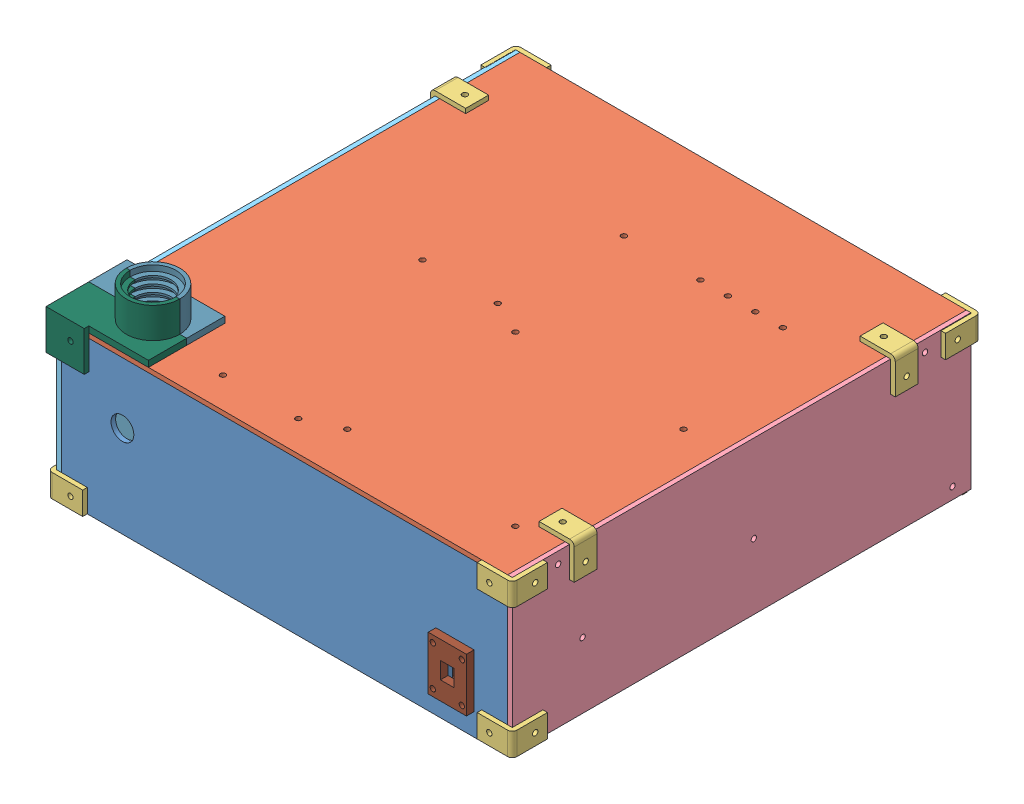
SolidWorks assembly Assem1, configuration Default. Lengths in mm.
Overall size (305.4 127.48 308.43).
27 component instances, 15 part files, 54 mates.
Components (placement in the parent):
- basen-1: basen [Default] at (-75.2142 166.4431 322.3397) size (292 100 3)
- wall2-1: wall2 [Default] at (-67.2142 269.4431 325.3397) x (0 0 -1) z (0 -1 0) size (300 292 3)
- holderr-2: holderr [Default] at (-61.7142 174.8603 22.3678) x (1 0 0) z (0 -0.061152 0.998128) size (23 15 23)
- baseupn-2: baseupn [Default] at (227.7858 169.4431 25.3397) x (0 0 1) z (-1 0 0) size (300 100 3)
- baseup-2: baseup [Default] at (-70.2142 169.4431 325.3397) x (0 0 -1) z (1 0 0) size (300 103 3)
- holderr-4: holderr [Default] at (231.1895 261.9431 33.8397) x (0 0 1) z (-1 0 0) size (23 15 23)
- holderr-5: holderr [Default] at (231.1895 173.9431 33.8397) x (0 0 1) z (-1 0 0) size (23 15 23) (hidden)
- holderr-6: holderr [Default] at (230.7858 176.9431 316.8397) x (0 0 -1) z (-1 0 0) size (23 15 23)
- holderr-8: holderr [Default] at (-73.2142 173.9431 316.8397) x (0 0 -1) z (1 0 0) size (23 15 23)
- holderr-10: holderr [Default] at (230.7858 261.9431 316.8397) x (0 0 -1) z (-1 0 0) size (23 15 23)
- holderr-11: holderr [Default] at (-73.2142 261.9431 316.8397) x (0 0 -1) z (1 0 0) size (23 15 23) (hidden)
- holderr-12: holderr [Default] at (230.7858 261.9431 316.8397) x (0 0 -1) z (-1 0 0) size (23 15 23)
- holderr-13: holderr [Default] at (-61.3105 261.9431 22.3397) size (23 15 23)
- holderr-14: holderr [Default] at (230.7858 260.9431 280.3397) x (0 -1 0) z (-1 0 0) size (23 15 23)
- holderr-16: holderr [Default] at (230.7858 260.9431 70.3397) x (0 -1 0) z (-1 0 0) size (23 15 23)
- holderr-17: holderr [Default] at (-73.2142 260.9431 280.3397) x (0 -1 0) z (1 0 0) size (23 15 23) (hidden)
- holderr-18: holderr [Default] at (-61.7142 272.4431 70.3397) x (1 0 0) z (0 -1 0) size (23 15 23)
- dm542-1: dm542 [Standard] at (-67.2142 219.1943 136.2857) x (0 0 -1) z (1 0 0) size (118.3 34 87.5)
- 7 INCH DIN RAIL-1: 7 INCH DIN RAIL [Default] at (205.3497 266.4431 98.5353) x (0 0 -1) z (-1 0 0) size (30.97 8.39 182.88)
- driver-2: driver [Default] at (173.5548 266.4431 143.8531) x (0 0 -1) z (-1 0 0) size (91 55 90)
- left_sidee-1: left_sidee [Default] at (-74.8105 166.4431 25.3397) size (292 100 3)
- KART_HOLDER-1: KART_HOLDER [Default] at (91.2858 256.4431 293.8397) x (1 0 0) z (0 1 0) size (127 127 10)
- usb-1: usb [Default] at (177.7858 180.9431 325.3397) size (25 35 21)
- relay_support-1: relay_support [Default] at (73.1608 242.4431 315.0897) x (0 0 -1) z (0 1 0) size (150 60 24)
- relaasy-2: relaasy [Default] at (43.1608 262.4431 240.0897) x (0 0 1) z (0 -1 0) size (138 56 17.2)
- control_cable-3: control_cable [Default] at (0.7858 269.4431 267.3397) x (-1 0 0) z (0 1 0) size (64 25 44)
- control_cable_up-1: control_cable_up [Default] at (-65.2142 269.4431 333.3397) x (1 0 0) z (0 1 0) size (64 28 46)
Mates (geometry in assembly coordinates):
- Coincident6: coincident aligned: plane of basen-1 through (224.7858 166.4431 325.3397) normal (1 0 0); plane of wall2-1 through (224.7858 266.4431 325.3397) normal (1 0 0)
- Coincident7: coincident aligned: plane of basen-1 through (-75.2142 166.4431 325.3397) normal (0 0 1); plane of wall2-1 through (-67.2142 266.4431 325.3397) normal (0 0 1)
- Coincident12: coincident anti-aligned: plane of basen-1 through (-75.2142 266.4431 325.3397) normal (0 1 0); plane of wall2-1 through (-67.2142 266.4431 325.3397) normal (0 -1 0)
- Coincident24: coincident: plane of wall2-1 through (224.7858 266.4431 325.3397) normal (1 0 0); plane of baseupn-2 through (224.7858 169.4431 25.3397) normal (-1 0 0)
- Coincident26: coincident: plane of wall2-1 through (-67.2142 269.4431 325.3397) normal (0 1 0); plane of baseupn-2 through (224.7858 269.4431 25.3397) normal (0 1 0)
- Concentric5: concentric: cylinder of baseupn-2 through (217.7858 261.9431 37.3397) axis (1 0 0) radius 1.75; cylinder of holderr-4 through (208.1895 261.9431 37.3397) axis (1 0 0) radius 1.75
- Concentric9: concentric: cylinder of baseupn-2 through (217.7858 176.9431 37.3397) axis (1 0 0) radius 1.75; cylinder of holderr-5 through (208.1895 173.9431 37.3397) axis (1 0 0) radius 1.75
- Concentric10: concentric aligned: cylinder of baseupn-2 through (217.7858 176.9431 313.3397) axis (1 0 0) radius 1.75; cylinder of holderr-6 through (207.7858 176.9431 313.3397) axis (1 0 0) radius 1.75
- Coincident32: coincident: plane of wall2-1 through (-67.2142 269.4431 325.3397) normal (0 1 0); plane of baseup-2 through (-67.2142 269.4431 325.3397) normal (0 1 0)
- Concentric15: concentric aligned: cylinder of holderr-2 through (-50.2142 173.9431 37.3397) axis (-1 0 0) radius 1.75; cylinder of baseup-2 through (-67.2142 173.9431 37.3397) axis (-1 0 0) radius 1.75
- Concentric17: concentric aligned: cylinder of baseup-2 through (-67.2142 173.9431 313.3397) axis (-1 0 0) radius 1.75; cylinder of holderr-8 through (-50.2142 173.9431 313.3397) axis (-1 0 0) radius 1.75
- Concentric22: concentric aligned: cylinder of baseupn-2 through (217.7858 261.9431 313.3397) axis (1 0 0) radius 1.75; cylinder of holderr-10 through (207.7858 261.9431 313.3397) axis (1 0 0) radius 1.75
- Concentric29: concentric: cylinder of basen-1 through (215.7858 261.9431 325.3397) axis (0 0 -1) radius 1.75; cylinder of holderr-12 through (215.7858 261.9431 305.3397) axis (0 0 1) radius 1.75
- Concentric30: concentric: cylinder of baseupn-2 through (217.7858 261.9431 313.3397) axis (1 0 0) radius 1.75; cylinder of holderr-12 through (207.7858 261.9431 313.3397) axis (1 0 0) radius 1.75
- Concentric31: concentric: cylinder of baseup-2 through (-67.2142 261.9431 313.3397) axis (-1 0 0) radius 1.75; cylinder of holderr-11 through (-50.2142 261.9431 313.3397) axis (-1 0 0) radius 1.75
- Concentric32: concentric: cylinder of basen-1 through (-58.2142 261.9431 325.3397) axis (0 0 -1) radius 1.75; cylinder of holderr-11 through (-58.2142 261.9431 305.3397) axis (0 0 1) radius 1.75
- Concentric33: concentric: cylinder of baseup-2 through (-67.2142 261.9431 37.3397) axis (-1 0 0) radius 1.75; cylinder of holderr-13 through (-49.8105 261.9431 37.3397) axis (-1 0 0) radius 1.75
- Concentric35: concentric: cylinder of baseupn-2 through (224.7858 257.4431 280.3397) axis (1 0 0) radius 1.75; cylinder of holderr-14 through (207.7858 257.4431 280.3397) axis (1 0 0) radius 1.75
- Concentric36: concentric aligned: cylinder of wall2-1 through (215.7858 266.4431 280.3397) axis (0 1 0) radius 1.75; cylinder of holderr-14 through (215.7858 249.4431 280.3397) axis (0 1 0) radius 1.75
- Concentric37: concentric aligned: cylinder of wall2-1 through (215.7858 266.4431 70.3397) axis (0 1 0) radius 1.75; cylinder of holderr-16 through (215.7858 249.4431 70.3397) axis (0 1 0) radius 1.75
- Concentric38: concentric: cylinder of baseupn-2 through (224.7858 257.4431 70.3397) axis (1 0 0) radius 1.75; cylinder of holderr-16 through (207.7858 257.4431 70.3397) axis (1 0 0) radius 1.75
- Concentric39: concentric: cylinder of baseup-2 through (-67.2142 257.4431 280.3397) axis (-1 0 0) radius 1.75; cylinder of holderr-17 through (-50.2142 257.4431 280.3397) axis (-1 0 0) radius 1.75
- Concentric40: concentric: cylinder of wall2-1 through (-58.2142 266.4431 280.3397) axis (0 1 0) radius 1.75; cylinder of holderr-17 through (-58.2142 249.4431 280.3397) axis (0 1 0) radius 1.75
- Concentric41: concentric: cylinder of wall2-1 through (-58.2142 266.4431 70.3397) axis (0 1 0) radius 1.75; cylinder of holderr-18 through (-58.2142 249.4431 70.3397) axis (0 1 0) radius 1.75
- Concentric42: concentric: cylinder of baseup-2 through (-67.2142 257.4431 70.3397) axis (-1 0 0) radius 1.75; cylinder of holderr-18 through (-50.2142 257.4431 70.3397) axis (-1 0 0) radius 1.75
- Coincident34: coincident anti-aligned: plane of baseup-2 through (-67.2142 169.4431 325.3397) normal (1 0 0); plane of dm542-1 through (-67.2142 219.1943 136.2857) normal (-1 0 0)
- Concentric43: concentric aligned: cylinder of baseup-2 through (-97.2142 212.4431 71.3397) axis (1 0 0) radius 1.75; cylinder of dm542-1 through (-67.2142 212.4431 71.3397) axis (1 0 0) radius 2.25
- Concentric44: concentric aligned: cylinder of baseup-2 through (-97.2142 212.4431 183.3397) axis (1 0 0) radius 1.75; cylinder of dm542-1 through (-67.2142 212.4431 183.3397) axis (1 0 0) radius 2.25
- Coincident36: coincident anti-aligned: plane of wall2-1 through (-67.2142 266.4431 325.3397) normal (0 -1 0); plane of 7 INCH DIN RAIL-1 through (207.8897 266.4431 107.7637) normal (0 1 0)
- Concentric49: concentric: cylinder of wall2-1 through (174.7858 269.4431 95.3397) axis (0 -1 0) radius 1.75; cylinder of 7 INCH DIN RAIL-1 through (174.7858 266.4431 95.3397) axis (0 -1 0) radius 3.1166
- Coincident38: coincident anti-aligned: plane of wall2-1 through (-67.2142 266.4431 325.3397) normal (0 -1 0); plane of driver-2 through (83.5548 266.4431 143.8531) normal (0 1 0)
- Concentric50: concentric: cylinder of holderr-4 through (216.1895 261.9431 45.3397) axis (0 0 -1) radius 1.75; cylinder of left_sidee-1 through (216.1895 261.9431 28.3397) axis (0 0 -1) radius 1.75
- Concentric51: concentric: cylinder of holderr-5 through (216.1895 173.9431 45.3397) axis (0 0 -1) radius 1.75; cylinder of left_sidee-1 through (216.1895 173.9431 28.3397) axis (0 0 -1) radius 1.75
- Coincident39: coincident anti-aligned: plane of holderr-5 through (208.1895 181.4431 25.3397) normal (0 0 1); plane of left_sidee-1 through (-74.8105 166.4431 25.3397) normal (0 0 -1)
- Concentric52: concentric: cylinder of holderr-13 through (-57.8105 261.9431 45.3397) axis (0 0 -1) radius 1.75; cylinder of left_sidee-1 through (-57.8105 261.9431 28.3397) axis (0 0 -1) radius 1.75
- Concentric53: concentric anti-aligned: cylinder of wall2-1 through (199.7858 266.4431 185.3397) axis (0 1 0) radius 1.75; cylinder of KART_HOLDER-1 through (199.7858 269.4431 185.3397) axis (0 -1 0) radius 1.75
- Concentric54: concentric anti-aligned: cylinder of wall2-1 through (199.7858 266.4431 295.3397) axis (0 1 0) radius 1.75; cylinder of KART_HOLDER-1 through (199.7858 269.4431 295.3397) axis (0 -1 0) radius 1.75
- Coincident41: coincident anti-aligned: plane of wall2-1 through (-67.2142 266.4431 325.3397) normal (0 -1 0); plane of KART_HOLDER-1 through (91.2858 266.4431 293.8397) normal (0 1 0)
- Concentric55: concentric anti-aligned: cylinder of basen-1 through (199.7858 211.4431 332.3397) axis (0 0 -1) radius 1.75; cylinder of usb-1 through (199.7858 211.4431 325.3397) axis (0 0 1) radius 1.75
- Concentric56: concentric anti-aligned: cylinder of basen-1 through (199.7858 185.4431 332.3397) axis (0 0 -1) radius 1.75; cylinder of usb-1 through (199.7858 185.4431 325.3397) axis (0 0 1) radius 1.75
- Coincident42: coincident anti-aligned: plane of basen-1 through (-75.2142 166.4431 325.3397) normal (0 0 1); plane of usb-1 through (177.7858 180.9431 325.3397) normal (0 0 -1)
- Concentric58: concentric anti-aligned: cylinder of wall2-1 through (18.5358 266.4431 174.8397) axis (0 1 0) radius 1.75; cylinder of relay_support-1 through (18.5358 262.4431 174.8397) axis (0 -1 0) radius 3
- Concentric59: concentric anti-aligned: cylinder of wall2-1 through (67.7858 266.4431 174.8397) axis (0 1 0) radius 1.75; cylinder of relay_support-1 through (67.7858 266.4431 174.8397) axis (0 -1 0) radius 1.75
- Coincident43: coincident anti-aligned: plane of wall2-1 through (-67.2142 266.4431 325.3397) normal (0 -1 0); plane of relay_support-1 through (73.1608 266.4431 315.0897) normal (0 1 0)
- Coincident44: coincident anti-aligned: plane of relay_support-1 through (73.1608 262.4431 315.0897) normal (0 -1 0); plane of relaasy-2 through (43.1608 262.4431 240.0897) normal (0 1 0)
- Width1: width anti-aligned: plane of relaasy-2 through (57.8108 245.2431 306.3147) normal (0 0 1); plane of relaasy-2 through (57.8108 245.2431 173.8647) normal (0 0 -1); plane of relay_support-1 through (17.1608 262.4431 310.5897) normal (0 0 -1); plane of relay_support-1 through (17.1608 262.4431 169.5897) normal (0 0 1)
- Width2: width anti-aligned: plane of relay_support-1 through (69.1608 262.4431 310.5897) normal (-1 0 0); plane of relay_support-1 through (17.1608 262.4431 310.5897) normal (1 0 0); plane of relaasy-2 through (71.1608 260.9431 309.0897) normal (1 0 0); plane of relaasy-2 through (15.1608 260.9431 309.0897) normal (-1 0 0)
- Concentric63: concentric anti-aligned: cylinder of wall2-1 through (-32.2142 276.4431 300.3397) axis (0 -1 0) radius 16; cylinder of control_cable-3 through (-32.2142 269.4431 300.3397) axis (0 1 0) radius 15
- Coincident50: coincident: plane of baseup-2 through (-73.2142 169.4431 325.3397) normal (-1 0 0); plane of control_cable-3 through (-73.2142 269.4431 267.3397) normal (-1 0 0)
- Coincident51: coincident anti-aligned: plane of wall2-1 through (-67.2142 269.4431 325.3397) normal (0 1 0); plane of control_cable-3 through (0.7858 269.4431 267.3397) normal (0 -1 0)
- Coincident52: coincident: plane of baseup-2 through (-70.2142 169.4431 325.3397) normal (-1 0 0); line of control_cable-3 through (-70.2142 275.4431 300.3397) axis (0 0 -1)
- Coincident53: coincident anti-aligned: plane of baseup-2 through (-70.2142 169.4431 325.3397) normal (-1 0 0); plane of control_cable-3 through (-70.2142 249.4431 300.3397) normal (1 0 0)
- Concentric65: concentric aligned: cylinder of control_cable-3 through (-32.2142 269.4431 300.3397) axis (0 1 0) radius 15; cylinder of control_cable_up-1 through (-32.2142 269.4431 300.3397) axis (0 1 0) radius 15
- Coincident56: coincident anti-aligned: plane of wall2-1 through (-67.2142 269.4431 325.3397) normal (0 1 0); plane of control_cable_up-1 through (-65.2142 269.4431 333.3397) normal (0 -1 0)
